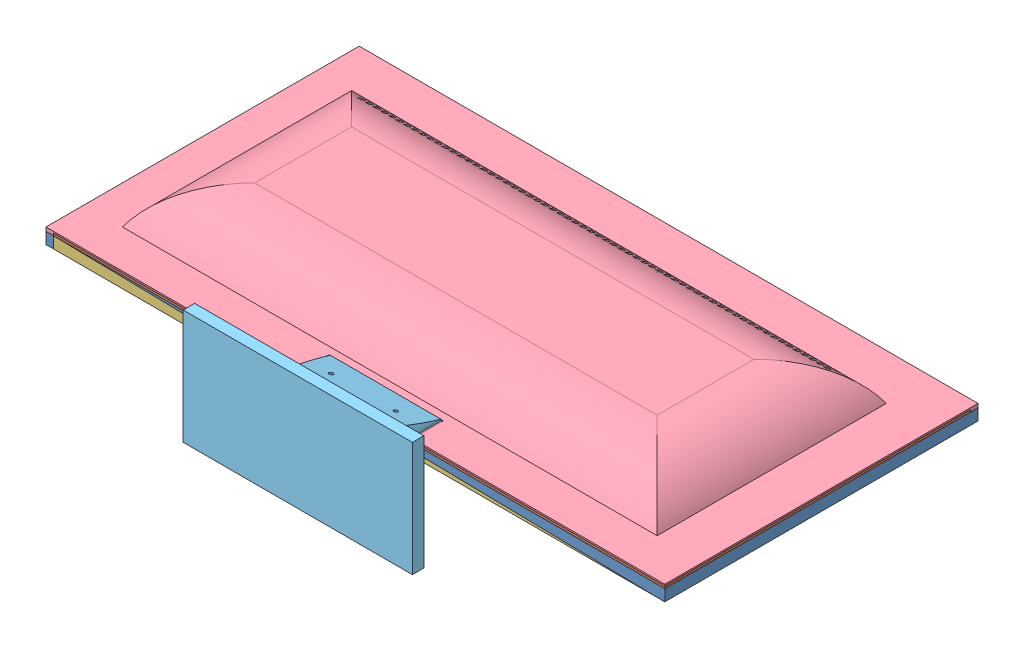
SolidWorks assembly Assem1, configuration Default. Lengths in mm.
Overall size (810 150 485.4).
5 component instances, 5 part files, 9 mates.
Components (placement in the parent):
- Front Panel-1: Front Panel [Default] at (-149.7645 429.1721 842.1158) size (810 15 410)
- Electric Circuit-1: Electric Circuit [Default] at (-139.7645 444.1721 842.1158) size (800 3 400)
- screen-1: screen [Default] at (-139.7645 429.1721 842.1158) size (800 15 400)
- TV Back-1: TV Back [Default] at (-149.7645 444.1721 842.1158) size (810 55 410)
- TV Holder-1: TV Holder [Default] at (105.2355 520.2275 917.5112) x (1 0 0) z (0 0 -1) size (300 150 115)
Mates (geometry in assembly coordinates):
- Coincident8: coincident aligned: line of Front Panel-1 through (-139.7645 444.1721 442.1158) axis (0 0 1); line of screen-1 through (-139.7645 444.1721 442.1158) axis (0 0 1)
- Coincident9: coincident aligned: line of Front Panel-1 through (-139.7645 444.1721 442.1158) axis (0 0 1); line of Electric Circuit-1 through (-139.7645 444.1721 442.1158) axis (0 0 1)
- Coincident10: coincident aligned: line of Front Panel-1 through (650.2355 444.1721 442.1158) axis (-1 0 0); line of screen-1 through (660.2355 444.1721 442.1158) axis (-1 0 0)
- Coincident11: coincident aligned: line of Front Panel-1 through (650.2355 444.1721 442.1158) axis (-1 0 0); line of Electric Circuit-1 through (660.2355 444.1721 442.1158) axis (-1 0 0)
- Coincident12: coincident aligned: line of Front Panel-1 through (-149.7645 444.1721 842.1158) axis (1 0 0); line of TV Back-1 through (-149.7645 444.1721 842.1158) axis (1 0 0)
- Coincident15: coincident aligned: line of Front Panel-1 through (660.2355 444.1721 842.1158) axis (0 0 -1); line of TV Back-1 through (660.2355 444.1721 842.1158) axis (0 0 -1)
- Parallel5: parallel anti-aligned: plane of TV Back-1 through (-149.7645 449.1721 842.1158) normal (0 1 0); plane of TV Holder-1 through (182.7355 440.2275 802.5112) normal (0 -1 0)
- Width1: width anti-aligned: plane of TV Holder-1 through (327.7355 440.2275 802.5112) normal (1 0 0); plane of TV Holder-1 through (182.7355 440.2275 802.5112) normal (-1 0 0); plane of TV Back-1 through (330.2355 448.1721 802.1158) normal (-1 0 0); plane of TV Back-1 through (180.2355 448.1721 802.1158) normal (1 0 0)
- Parallel6: parallel anti-aligned: plane of TV Back-1 through (-149.7645 449.1721 842.1158) normal (0 1 0); plane of TV Holder-1 through (182.7355 440.2275 802.5112) normal (0 -1 0)
